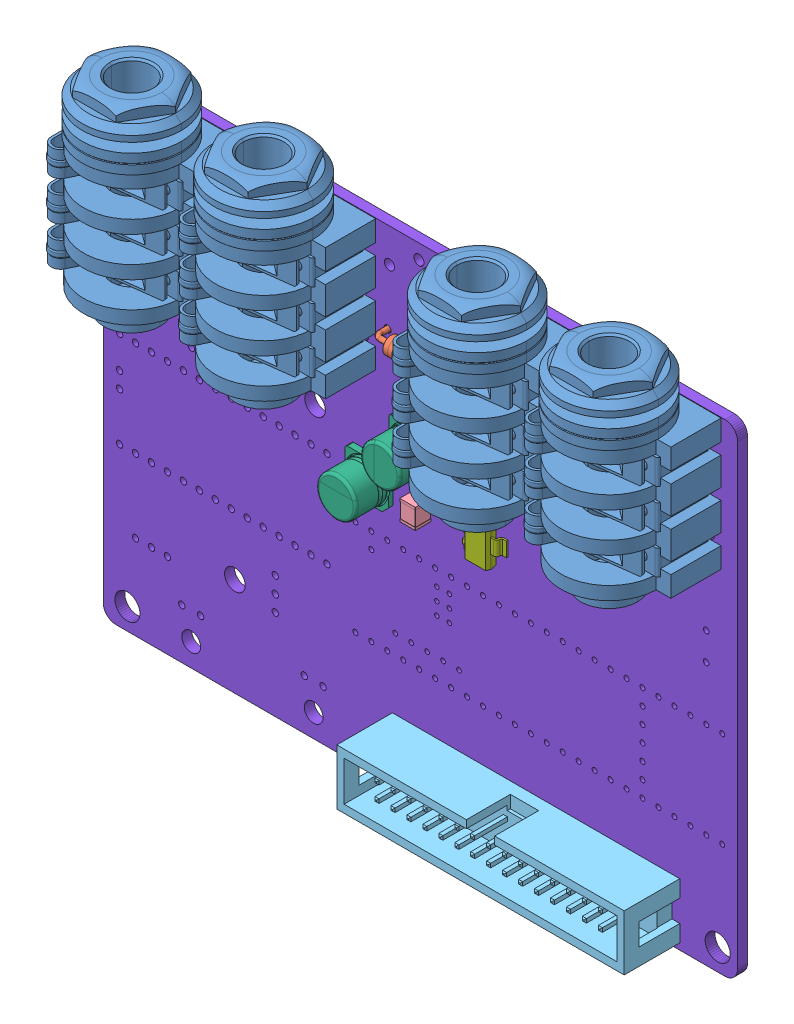
SolidWorks assembly teensy-dsp, configuration Default. Lengths in mm.
Overall size (101 84.91 19.7).
24 component instances, 8 part files, 0 mates.
Components (placement in the parent):
- teensy-dsp.step-1: teensy-dsp.step [Default] at origin size (101 84.91 19.7)
  - ACJS-IH--3DModel-STEP-56544.step-1: ACJS-IH--3DModel-STEP-56544.step [Default] at (168.5834 -75.1527 1.63) x (1 0 0) z (0 -1 0) size (20 19.7 33)
    - COMPOUND.step-1: COMPOUND.step [Default] at origin size (20 19.7 33)
  - ACJS-IH--3DModel-STEP-56544.step-2: ACJS-IH--3DModel-STEP-56544.step [Default] at (189.5834 -75.1527 1.63) x (1 0 0) z (0 -1 0) size (20 19.7 33)
    - COMPOUND.step-1: COMPOUND.step [Default] at origin size (20 19.7 33)
  - D_DO-41_SOD81_P10.16mm_Horizontal.step-1: D_DO-41_SOD81_P10.16mm_Horizontal.step [Default] at (146.4436 -79 1.63) size (10.96 2.72 5.71)
    - SOLID.step-1: SOLID.step [Default] at origin size (10.96 2.72 5.71)
  - R_1210_3225Metric.step-1: R_1210_3225Metric.step [Default] at (151.16 -85 1.63) size (3.2 2.5 0.55)
    - SOLID-0.step-1: SOLID-0.step [Default] at origin size (3.2 2.5 0.55)
  - C_1210_3225Metric.step-1: C_1210_3225Metric.step [Default] at (152.16 -100.4527 1.63) x (0 1 0) z (0 0 1) size (3.2 2.5 2.5)
    - SOLID-1.step-1: SOLID-1.step [Default] at origin size (3.2 2.5 2.5)
  - IDC-Header_2x15_P2.54mm_Vertical.step-1: IDC-Header_2x15_P2.54mm_Vertical.step [Default] at (188.16 -134.4167 1.63) x (0 -1 0) z (0 0 1) size (9.1 45.76 12.1)
    - SOLID-2.step-1: SOLID-2.step [Default] at origin size (9.1 45.76 12.1)
  - CP_Elec_6.3x5.9.step-1: CP_Elec_6.3x5.9.step [Default] at (151.16 -92.6527 1.63) x (-1 0 0) z (0 0 1) size (8.61 8.6 5.9)
    - SOLID-3.step-1: SOLID-3.step [Default] at origin size (8.61 8.6 5.9)
  - SOT-223.step-1: SOT-223.step [Default] at (162.16 -99.6527 1.63) size (7 6.5 1.7)
    - SOLID-4.step-1: SOLID-4.step [Default] at origin size (7 6.5 1.7)
  - CP_Elec_6.3x5.9.step-2: CP_Elec_6.3x5.9.step [Default] at (144.16 -100.4527 1.63) x (0 1 0) z (0 0 1) size (8.61 8.6 5.9)
    - SOLID-3.step-1: SOLID-3.step [Default] at origin size (8.61 8.6 5.9)
  - ACJS-IH--3DModel-STEP-56544.step-3: ACJS-IH--3DModel-STEP-56544.step [Default] at (134.5834 -75.1527 1.63) x (1 0 0) z (0 -1 0) size (20 19.7 33)
    - COMPOUND.step-1: COMPOUND.step [Default] at origin size (20 19.7 33)
  - ACJS-IH--3DModel-STEP-56544.step-4: ACJS-IH--3DModel-STEP-56544.step [Default] at (113.5834 -75.1527 1.63) x (1 0 0) z (0 -1 0) size (20 19.7 33)
    - COMPOUND.step-1: COMPOUND.step [Default] at origin size (20 19.7 33)
  - PCB.step-1: PCB.step [Default] at origin size (101 76.76 1.58)
